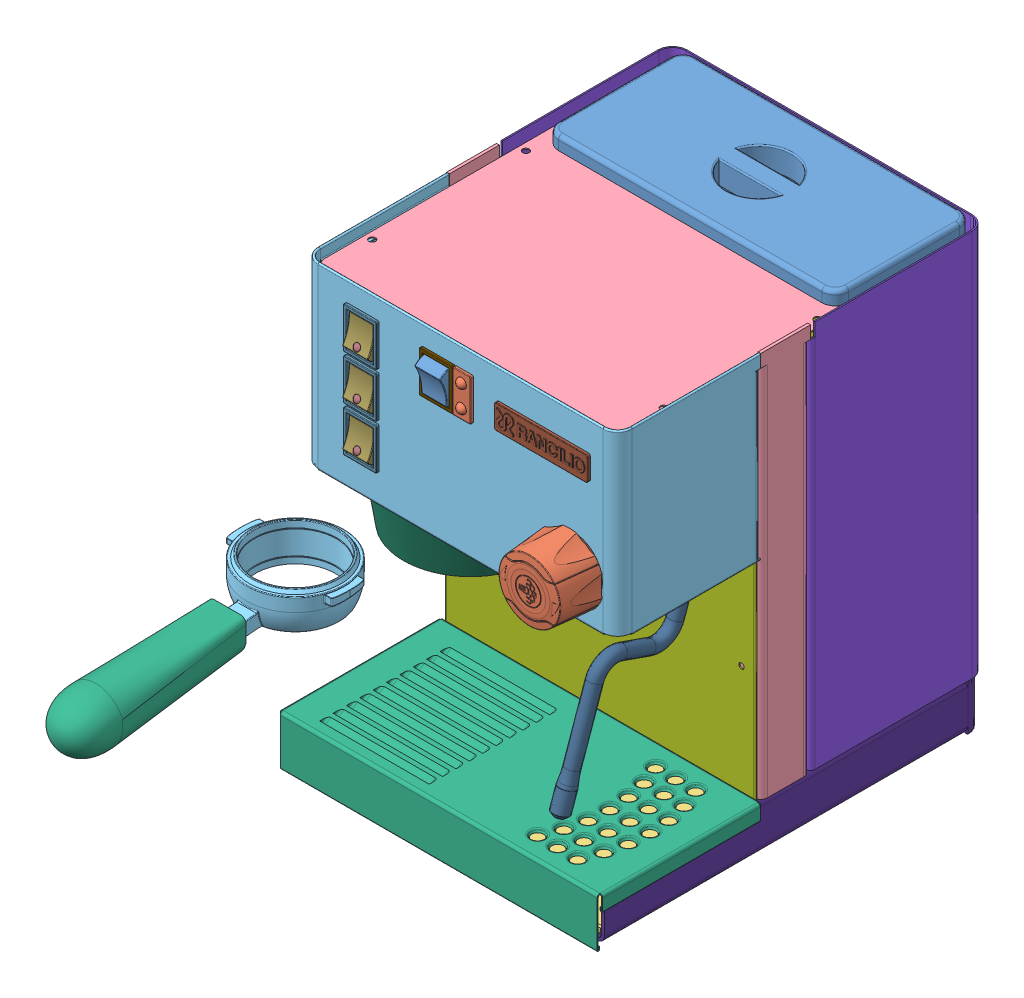
SolidWorks assembly Assembly, configuration Default. Lengths in mm.
Overall size (279.08 378 463.51).
42 component instances, 34 part files, 25 mates.
Components (placement in the parent):
- waterCover-1: waterCover [Default] at (126.4 164.8677 263.6788) x (-1 0 0) z (0 0 -1) size (217 20 103)
- knob-1: knob [Default] at (211.1757 73.9916 521.225) size (52.42 53.92 94.28)
- bin-1: bin [Default] at (127.0929 -35.6834 262.9213) size (208 204 94)
- topCover-1: topCover [Default] at (124.164 164.3166 349.3788) size (229 4.5 265.54)
- frontPanel-1: frontPanel [Default] at (124.1757 38.7916 484.7654) size (235 134.72 107)
- dripTrayCover-1: dripTrayCover [Default] at (125.2008 -152.9276 501.3369) size (241.1 37.05 122.05)
- dripTray-1: dripTray [Default] at (101.6044 -202.2301 322.5452) size (109.9 18.4 0)
- frontLowerPanel-1: frontLowerPanel [Default] at (123.362 -44.3995 379.8154) size (232.05 163.03 2.05)
- GroupHeadPanel-1: GroupHeadPanel [Default] at (124.121 38.6916 430.7654) size (232.4 0.9 104.4)
- spacingRing-1: spacingRing [Default] at (211.1757 73.9916 486.1631) size (28.36 28.36 15.44)
- steamWand-1: steamWand [Default] at (210.8231 1.6431 410.9317) x (0.999677 -0.004586 0.024987) z (-0.02224 0.31741 0.948028) size (19.78 155.7 68.45)
- logo-1: logo [Default] at (186.2622 140.8142 484.7654) size (70.1 18.1 2.93)
- switch-1: switch [Default] at (50.7819 140.3191 477.3211) x (1 0 0) z (0 0.243934 0.969792) size (19.03 25.28 11)
- indicator-1: indicator [Default] at (50.7819 135.8618 488.8928) x (1 0 0) z (0 -0.905429 0.424497) size (5 2.4 5)
- switchHousing-1: switchHousing [Default] at (50.7257 141.3916 464.7654) size (25 31 22)
- switchHousing-2: switchHousing [Default] at (50.7257 107.8916 464.7654) size (25 31 22)
- switchHousing-3: switchHousing [Default] at (50.7257 74.3916 464.7654) size (25 31 22)
- indicator-2: indicator [Default] at (50.7819 102.3618 488.8928) x (1 0 0) z (0 -0.905429 0.424497) size (5 2.4 5)
- indicator-3: indicator [Default] at (50.7819 68.8618 488.8928) x (1 0 0) z (0 -0.905429 0.424497) size (5 2.4 5)
- switch-2: switch [Default] at (50.7819 106.8191 477.3211) x (1 0 0) z (0 0.243934 0.969792) size (19.03 25.28 11)
- switch-3: switch [Default] at (50.7819 73.3191 477.3211) x (1 0 0) z (0 0.243934 0.969792) size (19.03 25.28 11)
- groupHeadCover-1: groupHeadCover [Default] at (72.7455 2.2169 378.9327) size (112.08 34 103.69)
- hexNut-1: hexNut [Default] at (211.3082 30.3529 399.6658) size (22 20 25.4)
- midCasing-1: midCasing [Default] at (124.0368 -136.7118 210.7093) size (231 36 284)
- switchHousingLarge-1: switchHousingLarge [Default] at (107.4757 141.3916 464.7654) size (25 31 22)
- switchLarge-1: switchLarge [Default] at (107.4503 142.2296 479.8688) x (1 0 0) z (0 -0.25038 0.968148) size (19.03 25.28 10.92)
- powerLight-1: powerLight [Default] at (126.8507 141.3916 484.2654) size (13.75 31 5.4)
- bottomCasing-1: bottomCasing [Default] at (123.7992 -122.7118 272.8481) size (226 32 281.85)
- topCase-1: topCase [Default] at (124.1757 21.6882 340.4654) size (235 290.4 70.3)
- portaHolder-1: portaHolder [Default] at (7.9842 -45.231 492.243) size (82.63 33.27 98.86)
- portaHandle-1: portaHandle [Default] at (8.453 -40.5852 543.4598) size (40.54 40.7 128.63)
- rearCase-1: rearCase [Default] at (124.5447 -36.8411 306.2397) size (225 200 1)
- backPanel-1: backPanel [Default] at (124.0539 26.7613 208.6389) size (235 290 131.83)
- esp32-1: esp32 [Default] at (219.3688 -25.0145 283.2197) x (0 -1 0) z (1 0 0) size (72.9 25.6 26) (hidden)
- pressureSensorGP300-1: pressureSensorGP300 [Default] at (177.2911 72.5291 265.8589) size (24 76 24) (hidden)
- ulkaPump-2: ulkaPump [Default] at (107.8051 -120.5618 288.8466) x (0 0 -1) z (1 0 0) size (50.6 66.66 136.68)
  - pumpConnector-1: pumpConnector [Default] at (-0.7849 39 13.5713) size (46.5 25 27.17)
  - pumpHolder-1: pumpHolder [Default] at (-0.7849 0 54.5393) size (34 51 27.6)
  - pumpHolder-2: pumpHolder [Default] at (-0.7849 0 -54.5393) x (-1 0 0) z (0 0 -1) size (34 51 27.6)
  - pumpHousing-1: pumpHousing [Default] at (-1.3746 43.1623 -13.3528) size (47 52.39 43.6)
  - pumpFrame-1: pumpFrame [Default] at (-0.8394 24.0944 -13.5787) size (50.6 32 54.3)
  - pumpInputConnector-1: pumpInputConnector [Default] at (-0.7849 39 -44.7393) size (11 20.04 18)
Mates (geometry in assembly coordinates):
- Coincident1: coincident anti-aligned: plane of topCover-1 through (124.164 164.3166 482.9154) normal (0 0 1); plane of frontPanel-1 through (230.8757 162.7166 482.9154) normal (0 0 -1)
- Coincident2: coincident anti-aligned: plane of topCover-1 through (238.664 163.5166 481.3788) normal (0 -1 0); plane of frontPanel-1 through (124.1757 163.5166 484.7654) normal (0 1 0)
- Coincident3: coincident anti-aligned: plane of frontPanel-1 through (124.1757 37.7916 484.7654) normal (0 1 0); plane of GroupHeadPanel-1 through (240.321 37.7916 482.9654) normal (0 -1 0)
- Coincident6: coincident aligned: line of frontPanel-1 through (230.3757 37.7916 482.9654) axis (-1 0 0); line of GroupHeadPanel-1 through (231.121 37.7916 482.9654) axis (-1 0 0)
- Concentric1: concentric aligned: cylinder of frontPanel-1 through (211.1757 73.9916 377.7654) axis (0 0 1) radius 12.7; cylinder of spacingRing-1 through (211.1757 73.9916 486.1631) axis (0 0 1) radius 12.75
- Coincident7: coincident anti-aligned: plane of frontPanel-1 through (124.1757 170.7916 484.7654) normal (0 0 1); plane of spacingRing-1 through (223.8016 75.7661 484.7654) normal (0 0 -1)
- Concentric2: concentric aligned: cylinder of knob-1 through (211.1757 73.9916 521.225) axis (0 0 1) radius 9; cylinder of spacingRing-1 through (211.1757 73.9916 486.1631) axis (0 0 1) radius 11
- Coincident8: coincident anti-aligned: plane of bin-1 through (127.0929 164.3166 262.9213) normal (0 -1 0); plane of topCover-1 through (238.664 164.3166 481.3788) normal (0 1 0)
- Coincident9: coincident anti-aligned: plane of frontPanel-1 through (124.1757 170.7916 484.7654) normal (0 0 1); plane of logo-1 through (186.2622 140.8142 484.7654) normal (0 0 -1)
- Coincident10: coincident anti-aligned: plane of switchYesIndicator-1 through (50.7819 135.8618 488.8928) normal (0 0.424497 0.905429); plane of indicator-1 through (48.2819 135.8618 488.8928) normal (0 -0.424497 -0.905429)
- Concentric3: concentric anti-aligned: circle of switchYesIndicator-1; circle of indicator-1
- Coincident11: coincident anti-aligned: plane of frontPanel-1 through (124.1757 170.7916 484.7654) normal (0 0 1); plane of switchHousing-1 through (50.7257 141.3916 484.7654) normal (0 0 -1)
- Coincident12: coincident aligned: line of frontPanel-1 through (39.9757 155.1416 484.7654) axis (0 -1 0); line of switchHousing-1 through (39.9757 155.1416 484.7654) axis (0 -1 0)
- Coincident13: coincident aligned: line of frontPanel-1 through (61.4757 155.1416 484.7654) axis (-1 0 0); line of switchHousing-1 through (61.4757 155.1416 484.7654) axis (-1 0 0)
- Tangent1: tangent anti-aligned: cylinder of switchYesIndicator-1 through (60.2819 140.6416 481.2274) axis (-1 0 0) radius 12; plane of switchHousing-1 through (40.9757 128.6416 465.7654) normal (0 1 0)
- Coincident14: coincident aligned: line of frontPanel-1 through (94.9757 127.6416 484.7654) axis (1 0 0); line of switchHousingLarge-1 through (96.7257 127.6416 484.7654) axis (1 0 0)
- Coincident15: coincident aligned: line of frontPanel-1 through (94.9757 155.1416 484.7654) axis (0 -1 0); line of switchHousingLarge-1 through (94.9757 155.8916 484.7654) axis (0 -1 0)
- Tangent2: tangent anti-aligned: plane of switchHousingLarge-1 through (97.7257 128.6416 465.7654) normal (0 1 0); cylinder of switchLarge-1 through (116.9503 140.6416 483.4523) axis (-1 0 0) radius 12
- Coincident17: coincident aligned: line of frontPanel-1 through (131.9757 127.6416 484.7654) axis (0 1 0); line of powerLight-1 through (131.9757 127.6416 484.7654) axis (0 1 0)
- Coincident18: coincident aligned: line of frontPanel-1 through (94.9757 127.6416 484.7654) axis (1 0 0); line of powerLight-1 through (121.7257 127.6416 484.7654) axis (1 0 0)
- Coincident19: coincident aligned: plane of frontPanel-1 through (124.1757 38.7916 377.7654) normal (0 0 -1); plane of frontLowerPanel-1 through (236.3745 -44.3995 377.7654) normal (0 0 -1)
- Coincident20: coincident anti-aligned: plane of midCasing-1 through (124.0368 -152.5618 210.7093) normal (0 1 0); plane of bottomCasing-1 through (123.7992 -152.5618 272.8481) normal (0 -1 0)
- Coincident22: coincident aligned: plane of frontPanel-1 through (6.6757 170.7916 484.7654) normal (-1 0 0); plane of topCase-1 through (6.6757 21.6882 340.4654) normal (-1 0 0)
- Coincident23: coincident anti-aligned: plane of frontPanel-1 through (124.1757 38.7916 377.7654) normal (0 0 -1); plane of topCase-1 through (124.1757 21.6882 377.7654) normal (0 0 1)
- Coincident24: coincident anti-aligned: plane of bottomCasing-1 through (236.7992 -120.5618 210.8481) normal (0 1 0); plane of ulkaPump-2/pumpHolder-1 through (162.3443 -120.5618 289.6315) normal (0 -1 0)
